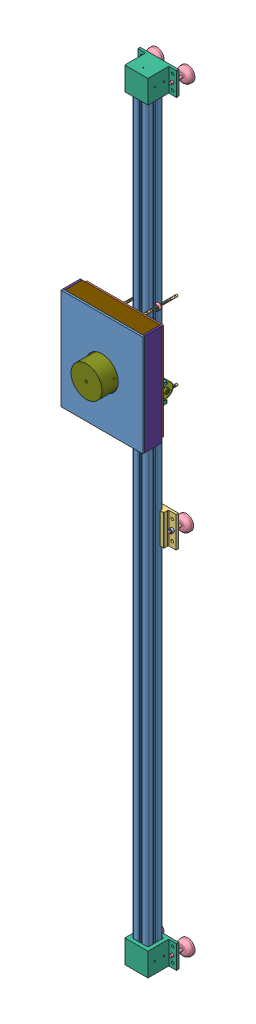
SolidWorks assembly assemblagecompletP2, configuration Défaut. Lengths in mm.
Overall size (212 2020 221.59).
75 component instances, 25 part files, 30 mates.
Components (placement in the parent):
- rail-1: rail [Défaut] at (-24.0212 110.7646 2000) size (40 2000 40)
- suppport ameliore-1: suppport ameliore [Défaut] at (-123.9247 615.4062 2058.0867) size (200 250 10)
- TigeFilet-1: TigeFilet [Défaut] at (-48.9247 590.4062 2068.0867) x (1 0 0) z (0 1 0) size (5.15 120.44 5.77)
- TigeFilet-2: TigeFilet [Défaut] at (1.0753 590.4062 2068.7589) x (-0.923728 -0.383049 0) z (0.383049 -0.923728 0) size (5.15 120.44 5.77)
- TigeFilet-3: TigeFilet [Défaut] at (1.0753 390.4062 2068.0961) x (-0.923728 -0.383049 0) z (0.383049 -0.923728 0) size (5.15 120.44 5.77)
- TigeFilet-4: TigeFilet [Défaut] at (-48.9247 390.4062 2068.4052) x (-0.728868 0.684654 0) z (-0.684654 -0.728868 0) size (5.15 120.44 5.77)
- RoueVAssemblage1-1: RoueVAssemblage1 [Défaut] at (-46.4189 589.2628 1984.8207) x (0.996447 0.084223 0) z (0 0 1) size (15.2 15.2 9)
  - RoueV1-1: RoueV1 [Défaut] at (-2.4006 1.3504 10.7) size (15.2 15.2 9)
  - RoueV2-1: RoueV2 [Défaut] at (-2.4006 1.3504 10.7) x (0.999854 -0.017094 0) z (0 0 1) size (10 10 9)
- SousAssemblageMoteurComplet-1: SousAssemblageMoteurComplet [Défaut] at (-133.3233 760.2443 1925.5591) x (1 0 0) z (0 -1 0) size (134.9 58.55 89.71)
  - MoteurEtSupport-1: MoteurEtSupport [Défaut] at (175.3767 115.3051 355.1381) x (0 1 0) z (0 0 -1) size (42.55 57.9 70)
    - SupportMoteur-1: SupportMoteur [Défaut] at (-2.7774 -21.4781 70) size (42.55 52 70)
    - Moteur-1: Moteur [Défaut] at (-4.7774 18.5219 45) x (1 0 0) z (0 -1 0) size (35.75 35.75 56.7)
  - piecemaintientchariot-1: piecemaintientchariot [Défaut] at (103.8575 100.6487 331.5754) size (50 31.79 18)
  - RoulementàBilles-1: RoulementàBilles [Défaut] at (106.8021 108.7409 335.5754) size (4 10 10)
  - Tige_entre_roues-1: Tige_entre_roues [Défaut] at (63.9986 108.7409 335.5754) size (80 3 3)
  - RoueAssemblee-1: RoueAssemblee [Défaut] at (119.9243 114.0834 363.6739) x (-1 0 0) z (0 -0.197919 -0.980218) size (16.9 28.6 28.6)
    - Roue1-1: Roue1 [Défaut] at (-7.3778 0.3244 28.6) size (13 28.6 28.6)
    - Roue2-1: Roue2 [Défaut] at (-7.6778 0.3244 28.6) x (0 -1 0) z (0 0 1) size (19 16.9 19)
  - RoueAssemblee-2: RoueAssemblee [Défaut] at (98.6799 108.2781 306.9773) x (1 0 0) z (0 0.004838 0.999988) size (16.9 28.6 28.6)
    - Roue1-1: Roue1 [Défaut] at (-7.3778 0.3244 28.6) size (13 28.6 28.6)
    - Roue2-1: Roue2 [Défaut] at (-7.6778 0.3244 28.6) x (0 -1 0) z (0 0 1) size (19 16.9 19)
  - PEngrenage-1: PEngrenage [Défaut] at (140.9986 110.5276 310.1381) x (1 0 0) z (0 0.064382 0.997925) size (7.5 9 9)
  - Gengrenage-1: Gengrenage [Défaut] at (143.9986 108.7409 335.5754) x (0 -0.815974 -0.578088) z (0 0.578088 -0.815974) size (42 8.4 42)
- SousAssemblageMoteurComplet-2: SousAssemblageMoteurComplet [Défaut] at (85.4739 220.5681 1925.5591) x (-1 0 0) z (0 1 0) size (134.9 58.55 89.71)
  - MoteurEtSupport-1: MoteurEtSupport [Défaut] at (175.3767 115.3051 355.1381) x (0 1 0) z (0 0 -1) size (42.55 57.9 70)
    - SupportMoteur-1: SupportMoteur [Défaut] at (-2.7774 -21.4781 70) size (42.55 52 70)
    - Moteur-1: Moteur [Défaut] at (-4.7774 18.5219 45) x (1 0 0) z (0 -1 0) size (35.75 35.75 56.7)
  - piecemaintientchariot-1: piecemaintientchariot [Défaut] at (103.8575 100.6487 331.5754) size (50 31.79 18)
  - RoulementàBilles-1: RoulementàBilles [Défaut] at (106.8021 108.7409 335.5754) size (4 10 10)
  - Tige_entre_roues-1: Tige_entre_roues [Défaut] at (63.9986 108.7409 335.5754) size (80 3 3)
  - RoueAssemblee-1: RoueAssemblee [Défaut] at (119.9243 114.0834 363.6739) x (-1 0 0) z (0 -0.197919 -0.980218) size (16.9 28.6 28.6)
    - Roue1-1: Roue1 [Défaut] at (-7.3778 0.3244 28.6) size (13 28.6 28.6)
    - Roue2-1: Roue2 [Défaut] at (-7.6778 0.3244 28.6) x (0 -1 0) z (0 0 1) size (19 16.9 19)
  - RoueAssemblee-2: RoueAssemblee [Défaut] at (98.6799 108.2781 306.9773) x (1 0 0) z (0 0.004838 0.999988) size (16.9 28.6 28.6)
    - Roue1-1: Roue1 [Défaut] at (-7.3778 0.3244 28.6) size (13 28.6 28.6)
    - Roue2-1: Roue2 [Défaut] at (-7.6778 0.3244 28.6) x (0 -1 0) z (0 0 1) size (19 16.9 19)
  - PEngrenage-1: PEngrenage [Défaut] at (140.9986 110.5276 310.1381) x (1 0 0) z (0 0.064382 0.997925) size (7.5 9 9)
  - Gengrenage-1: Gengrenage [Défaut] at (143.9986 108.7409 335.5754) x (0 -0.815974 -0.578088) z (0 0.578088 -0.815974) size (42 8.4 42)
- RoueVAssemblage1-2: RoueVAssemblage1 [Défaut] at (-47.7266 392.8863 1984.6734) x (-0.062339 0.998055 0) z (0 0 1) size (15.2 15.2 9)
  - RoueV1-1: RoueV1 [Défaut] at (-2.4006 1.3504 10.7) size (15.2 15.2 9)
  - RoueV2-1: RoueV2 [Défaut] at (-2.4006 1.3504 10.7) x (0.999854 -0.017094 0) z (0 0 1) size (10 10 9)
- RoueVAssemblage1-3: RoueVAssemblage1 [Défaut] at (3.4744 589.0531 1984.6118) x (0.999999 -0.001144 0) z (0 0 1) size (15.2 15.2 9)
  - RoueV1-1: RoueV1 [Défaut] at (-2.4006 1.3504 10.7) size (15.2 15.2 9)
  - RoueV2-1: RoueV2 [Défaut] at (-2.4006 1.3504 10.7) x (0.999854 -0.017094 0) z (0 0 1) size (10 10 9)
- RoueVAssemblage1-4: RoueVAssemblage1 [Défaut] at (3.7583 389.7831 1984.8978) x (0.959883 0.2804 0) z (0 0 1) size (15.2 15.2 9)
  - RoueV1-1: RoueV1 [Défaut] at (-2.4006 1.3504 10.7) size (15.2 15.2 9)
  - RoueV2-1: RoueV2 [Défaut] at (-2.4006 1.3504 10.7) x (0.999854 -0.017094 0) z (0 0 1) size (10 10 9)
- SupportCamera_Assemblage_V1-1: SupportCamera_Assemblage_V1 [Défaut] at (42.0768 573.8422 2099.1211) x (1 0 0) z (0 -1 0) size (96.67 90 96.67)
  - SupportCamera_Base_V1-1: SupportCamera_Base_V1 [Défaut] at (-66.3336 -31.0344 85) size (85 75 85)
  - SupportCamera_Haut_V1-1: SupportCamera_Haut_V1 [Défaut] at (-66.3336 43.9656 85) x (0.97155 0 -0.236833) z (0.236833 0 0.97155) size (80 45 80)
- CacheChariotAssemblage-2: CacheChariotAssemblage [Défaut] at (353.2431 476.4609 2057.2625) x (0 -1 0) z (-1 0 0) size (262 50 212)
  - CacheLateral-1: CacheLateral [Défaut] at (-145.0812 10.8242 271.5) size (262 45 5)
  - CacheLateral2-1: CacheLateral2 [Défaut] at (-140.0812 55.8242 276.5) x (0 0 1) z (0 -1 0) size (202 5 45)
  - CacheLateral-2: CacheLateral [Défaut] at (-145.0812 10.8242 478.5) size (262 45 5)
  - CacheLateral2-2: CacheLateral2 [Défaut] at (111.9188 55.8242 478.5) x (0 0 -1) z (0 -1 0) size (202 5 45)
  - Pièce3^CacheChariotAssemblage-1: Pièce3^CacheChariotAssemblage [Défaut] at origin (virtual)
  - CacheHaut-1: CacheHaut [Défaut] at (116.9188 60.8242 271.5) x (0 0 1) z (0 -1 0) size (212 262 5)
- RoueCodeuse-1: RoueCodeuse [Défaut] at (21.6397 556.1435 2034.3) x (0 0.924225 0.381849) z (-1 0 0) size (28.6 28.6 2)
- assemblage_maintient_entre_rail-1: assemblage_maintient_entre_rail [Défaut] at (28.8853 84.5102 1966.7227) x (1 0 0) z (0 -1 0) size (129.85 48.97 80)
  - piece_maintient_entre_rail-1: piece_maintient_entre_rail [Défaut] at (-82.9065 21.2773 40) size (100 18.3 80)
  - Pied-1: Pied [Défaut] at (-92.9065 17.3122 0) x (0.900255 0 -0.435364) z (0.435364 0 0.900255) size (38 45 38)
  - Pied-2: Pied [Défaut] at (-12.9065 17.6532 0) x (0.935976 0 -0.352064) z (0.352064 0 0.935976) size (38 45 38)
  - ecrou_M7-1: ecrou_M7 [Défaut] at (-92.9065 9.05 0) x (0.995992 0 -0.089439) z (0.089439 0 0.995992) size (11 5.5 11)
  - ecrou_M7-2: ecrou_M7 [Défaut] at (-92.9065 -2.574 0) x (0.999221 0 0.039466) z (-0.039466 0 0.999221) size (11 5.5 11)
  - ecrou_M7-3: ecrou_M7 [Défaut] at (-12.9065 9.3498 0) x (0.999844 0 -0.017652) z (0.017652 0 0.999844) size (11 5.5 11)
  - ecrou_M7-4: ecrou_M7 [Défaut] at (-12.9065 -2.2533 0) x (0.99851 0 -0.054578) z (0.054578 0 0.99851) size (11 5.5 11)
- Assemblagefinrail-2: Assemblagefinrail [Défaut] at (14.5886 1090.7646 2011.2866) x (1 0 0) z (0 -1 0) size (118 93 60)
  - piece_fin_rail-1: piece_fin_rail [Défaut] at (-8.1098 18.2134 30) size (100 60 60)
  - Pied-1: Pied [Défaut] at (-78.1098 -29.7866 0) size (38 45 38)
  - Pied-2: Pied [Défaut] at (1.8902 -29.7866 0) size (38 45 38)
- Assemblagefinrail-4: Assemblagefinrail [Défaut] at (-61.631 -869.2354 2011.2866) x (-1 0 0) z (0 1 0) size (118 93 60)
  - piece_fin_rail-1: piece_fin_rail [Défaut] at (-8.1098 18.2134 30) size (100 60 60)
  - Pied-1: Pied [Défaut] at (-78.1098 -29.7866 0) size (38 45 38)
  - Pied-2: Pied [Défaut] at (1.8902 -29.7866 0) size (38 45 38)
Mates (geometry in assembly coordinates):
- Coaxiale29: concentric: circle of TigeFilet-1; circle of RoueVAssemblage1-1/RoueV2-1
- Coaxiale31: concentric: cylinder of suppport ameliore-1 through (57.5753 420.1062 2068.0867) axis (0 0 1) radius 1.7; circle of SousAssemblageMoteurComplet-1/MoteurEtSupport-1/SupportMoteur-1
- Coïncidente3: coincident: plane of suppport ameliore-1 through (-123.9247 615.4062 2058.0867) normal (0 0 -1); plane of SousAssemblageMoteurComplet-1/MoteurEtSupport-1/SupportMoteur-1 through (65.5753 475.1062 2058.0867) normal (0 0 1)
- Coaxiale40: concentric: circle of suppport ameliore-1; circle of SousAssemblageMoteurComplet-2/MoteurEtSupport-1/SupportMoteur-1
- Coaxiale41: concentric: circle of suppport ameliore-1; cylinder of SousAssemblageMoteurComplet-2/MoteurEtSupport-1/SupportMoteur-1 through (-105.4247 560.7062 2063.0867) axis (0 0 -1) radius 1.2295
- Coïncidente5: coincident: plane of suppport ameliore-1 through (-123.9247 615.4062 2058.0867) normal (0 0 -1); plane of SousAssemblageMoteurComplet-2/MoteurEtSupport-1/SupportMoteur-1 through (-113.4247 505.7062 2058.0867) normal (0 0 1)
- Tangent4: tangent: plane of rail-1 through (-24.0212 1110.7646 2020) normal (0 0 1); cylinder of SousAssemblageMoteurComplet-1/RoueAssemblee-2/Roue1-1 through (-53.3626 424.6688 2034.3) axis (-1 0 0) radius 14.3
- Distance1: distance = 17.5 mm: plane of rail-1 through (-44.0212 1110.7646 2000) normal (-1 0 0); plane of SousAssemblageMoteurComplet-1/piecemaintientchariot-1 through (-26.5212 420.6688 2040.3) normal (-1 0 0)
- Parallèle19: parallel: plane of rail-1 through (-44.0212 1110.7646 2000) normal (-1 0 0); plane of suppport ameliore-1 through (-123.9247 615.4062 2068.0867) normal (-1 0 0)
- Coaxiale44: concentric: circle of suppport ameliore-1; circle of TigeFilet-1
- Perpendiculaire2: perpendicular: plane of rail-1 through (-24.0212 1110.7646 2020) normal (0 0 1); plane of suppport ameliore-1 through (-123.9247 615.4062 2068.0867) normal (0 1 0)
- Coaxiale45: concentric: circle of suppport ameliore-1; circle of TigeFilet-2
- Coaxiale46: concentric: circle of suppport ameliore-1; circle of TigeFilet-4
- Coaxiale47: concentric: circle of suppport ameliore-1; circle of TigeFilet-3
- Coaxiale48: concentric: circle of TigeFilet-4; circle of RoueVAssemblage1-2/RoueV2-1
- Coaxiale52: concentric: circle of TigeFilet-2; circle of RoueVAssemblage1-3/RoueV2-1
- Coaxiale53: concentric: circle of TigeFilet-3; circle of RoueVAssemblage1-4/RoueV2-1
- Coïncidente8: coincident: plane of suppport ameliore-1 through (-123.9247 615.4062 2068.0867) normal (0 0 1); plane of SupportCamera_Assemblage_V1-1/SupportCamera_Base_V1-1 through (-24.2569 488.8422 2068.0867) normal (0 0 -1)
- Distance3: distance = 69.6 mm: point of SupportCamera_Assemblage_V1-1/SupportCamera_Haut_V1-1; cylinder of suppport ameliore-1 through (-3.9247 555.4062 2068.0867) axis (0 0 -1) radius 1.3766
- Distance4: distance = 46.7 mm: point of SupportCamera_Assemblage_V1-1/SupportCamera_Haut_V1-1; cylinder of suppport ameliore-1 through (-69.4247 500.7062 2068.0867) axis (0 0 1) radius 1.7
- Coaxiale56: concentric: circle of SupportCamera_Assemblage_V1-1/SupportCamera_Haut_V1-1; circle of CacheChariotAssemblage-2/CacheHaut-1
- Coaxiale57: concentric: circle of SousAssemblageMoteurComplet-2/Tige_entre_roues-1; circle of RoueCodeuse-1
- Coïncidente9: coincident: plane of rail-1 through (-24.0212 1110.7646 1980) normal (0 0 -1); plane of assemblage_maintient_entre_rail-1/piece_maintient_entre_rail-1 through (-44.0212 124.5102 1980) normal (0 0 1)
- Coïncidente12: coincident: plane of rail-1 through (-24.0212 1110.7646 1980) normal (0 0 -1); plane of assemblage_maintient_entre_rail-1/piece_maintient_entre_rail-1 through (-44.0212 124.5102 1980) normal (0 0 1)
- Coaxiale58: concentric: cylinder of rail-1 through (-40.0212 1110.7646 1984) axis (0 -1 0) radius 4; cylinder of assemblage_maintient_entre_rail-1/piece_maintient_entre_rail-1 through (-40.0212 124.5102 1984) axis (0 1 0) radius 4
- Coïncidente13: coincident: plane of Assemblagefinrail-2/piece_fin_rail-1 through (-44.0212 1110.7646 2020) normal (1 0 0); plane of rail-1 through (-44.0212 1110.7646 2000) normal (-1 0 0)
- Coïncidente14: coincident: plane of rail-1 through (-24.0212 1110.7646 2020) normal (0 0 1); plane of Assemblagefinrail-2/piece_fin_rail-1 through (-44.0212 1110.7646 2020) normal (0 0 -1)
- Coïncidente22: coincident: plane of rail-1 through (-24.0212 -889.2354 2000) normal (0 -1 0); plane of Assemblagefinrail-4/piece_fin_rail-1 through (-53.5212 -889.2354 2115.9011) normal (0 1 0)
- Coïncidente23: coincident: plane of rail-1 through (-44.0212 1110.7646 2000) normal (-1 0 0); plane of Assemblagefinrail-4/piece_fin_rail-1 through (-44.0212 -889.2354 2106.4011) normal (1 0 0)
- Coaxiale61: concentric: cylinder of rail-1 through (-40.0212 1110.7646 2016) axis (0 -1 0) radius 4; cylinder of Assemblagefinrail-4/piece_fin_rail-1 through (-40.0212 -889.2354 2016) axis (0 -1 0) radius 4
